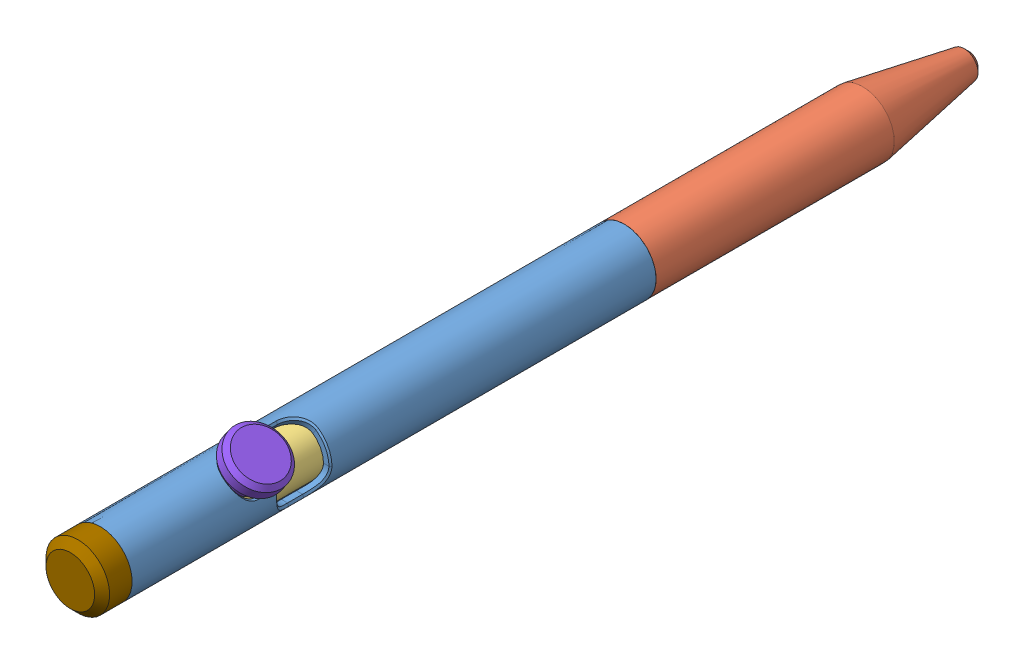
SolidWorks assembly Pen Assembly, configuration Default. Lengths in mm.
Overall size (16.77 17.97 152.65).
10 component instances, 9 part files, 11 mates.
Components (placement in the parent):
- Pen Shaft-1: Pen Shaft [Default] at (12.8073 62.304 63.1553) size (11.05 11.53 88.9)
- Pen Top-1: Pen Top [Default] at (12.8073 62.304 75.8553) x (-0.923728 -0.383049 0) z (0 0 -1) size (10.79 10.79 71.12)
- Slider Cylinder-1: Slider Cylinder [Default] at (12.8073 62.304 139.9903) x (-0.819152 0.573576 0) z (0 0 -1) size (8.26 8.26 22.23)
- Pen inkwell assembly-1: Pen inkwell assembly [Default] at (-12.86 42.3552 38.3311) x (1 0 0) z (0 1 0) size (6.31 113.28 6.31)
  - Pen ink tip-1: Pen ink tip [Default] at (25.6673 5.0658 19.9488) size (5 28 5)
  - Pen inkwell-1: Pen inkwell [Default] at (25.6673 -78.9342 19.9488) size (5 89 5)
  - pen roller ball-1: pen roller ball [Default] at (25.6673 33.0658 19.9488) x (0.127408 -0.669313 0.731975) z (-0.328988 -0.724728 -0.605422) size (1 1 1)
  - pen inkwell cap-1: pen inkwell cap [Default] at (25.6673 -75.9342 19.9488) x (-0.950016 0 -0.312203) z (-0.312203 0 0.950016) size (5 3.5 5)
- Slider Driver-2: Slider Driver [Default] at (18.4528 70.3665 130.4653) x (0.036853 -0.025805 0.998987) z (-0.573576 -0.819152 0) size (9.53 9.53 13.33)
- Pen Back-1: Pen Back [Default] at (12.8073 62.304 157.1353) x (-0.923728 -0.383049 0) z (0 0 -1) size (10.79 10.79 15.24)
Mates (geometry in assembly coordinates):
- Coincident2: coincident anti-aligned: plane of Pen Shaft-1 through (12.8073 62.304 63.1553) normal (0 0 -1); plane of Pen Top-1 through (12.8073 62.304 63.1553) normal (0 0 1)
- Concentric1: concentric aligned: circle of Pen Shaft-1; circle of Pen Top-1
- Concentric4: concentric anti-aligned: cylinder of Pen Shaft-1 through (12.8073 62.304 152.0553) axis (0 0 -1) radius 3.175; cylinder of Slider Cylinder-1 through (12.8073 62.304 117.7653) axis (0 0 1) radius 4.1275
- Coincident5: coincident anti-aligned: plane of Slider Cylinder-1 through (12.8073 62.304 117.7653) normal (0 0 -1); plane of Pen inkwell assembly-1/pen inkwell cap-1 through (12.8073 62.304 117.7653) normal (0 0 1)
- Concentric7: concentric anti-aligned: cylinder of Pen Shaft-1 through (12.8073 62.304 152.0553) axis (0 0 -1) radius 3.175; cylinder of Pen inkwell assembly-1/Pen inkwell-1 through (12.8073 62.304 28.2653) axis (0 0 1) radius 2.5
- Concentric17: concentric anti-aligned: cylinder of Slider Cylinder-1 through (15.1748 65.685 130.4653) axis (0.573576 0.819152 0) radius 2.0193; cylinder of Slider Driver-2 through (5.2297 51.4819 130.4653) axis (-0.573576 -0.819152 0) radius 1.905
- Concentric18: concentric aligned: cylinder of Pen Shaft-1 through (12.8073 62.304 152.0553) axis (0 0 1) radius 4.2164; cylinder of Pen Back-1 through (12.8073 62.304 141.8953) axis (0 0 1) radius 4.7625
- Coincident11: coincident anti-aligned: plane of Pen Shaft-1 through (12.8073 62.304 152.0553) normal (0 0 1); plane of Pen Back-1 through (12.8073 62.304 152.0553) normal (0 0 -1)
- Coincident14: coincident anti-aligned: plane of Slider Cylinder-1 through (14.4463 64.6447 130.4653) normal (0.573576 0.819152 0); plane of Slider Driver-2 through (14.4463 64.6447 130.4653) normal (-0.573576 -0.819152 0)
- Concentric20: concentric anti-aligned: cylinder of Pen Shaft-1 through (17.1191 68.4618 130.4653) axis (-0.573576 -0.819152 0) radius 3.175; cylinder of Slider Driver-2 through (14.4463 64.6447 130.4653) axis (0.573576 0.819152 0) radius 2.54
- Concentric21: concentric anti-aligned: cylinder of Pen Shaft-1 through (18.2048 62.304 124.1153) axis (-1 0 0) radius 3.175; cylinder of Slider Driver-2 through (15.6648 62.304 124.1153) axis (1 0 0) radius 2.54
